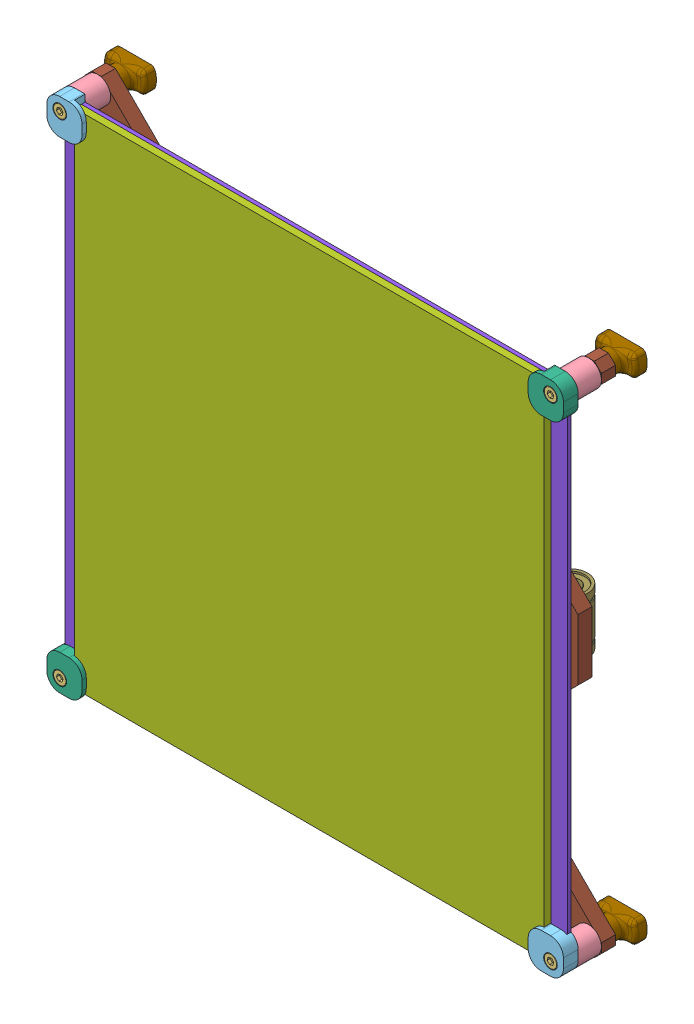
SolidWorks assembly Assembly y-carriage, configuration Valor predeterminado. Lengths in mm.
Overall size (227 224.47 49.2).
33 component instances, 14 part files, 82 mates.
Components (placement in the parent):
- Nut DIN 985 - M3-3: Nut DIN 985 - M3 [Valor predeterminado] at (-82.8364 -309.0808 -33.2819) x (0 0 -1) z (-0.999964 0.008433 0) size (4 6.35 5.5)
- Washer DIN 125A - M3-5: Washer DIN 125A - M3 [Valor predeterminado] at (-82.8364 -309.0808 -33.2819) x (0 0 -1) z (0.998771 -0.049562 0) size (0.5 7 7)
- Washer DIN 125A - M3-6: Washer DIN 125A - M3 [Valor predeterminado] at (-82.8364 -350.0808 -33.2819) x (0 0 -1) z (0.998771 -0.049562 0) size (0.5 7 7)
- Nut DIN 985 - M3-4: Nut DIN 985 - M3 [Valor predeterminado] at (-82.8364 -350.0808 -33.2819) x (0 0 -1) z (0.999227 -0.039315 0) size (4 6.35 5.5)
- Screw DIN 912 - M3 x 25 --- 18N-5: Screw DIN 912 - M3 x 25 --- 18N [Valor predeterminado] at (21.6636 -433.5808 -17.5819) x (0 0 1) z (-0.68344 0.730007 0) size (28 5.5 5.5)
- heatbed_spacer-5: heatbed_spacer [Valor predeterminado] at (-187.3364 -224.5808 -33.7819) x (-0.828895 0.559404 0) z (0 0 1) size (11 11 9.9)
- heatbed_holder_A-3: heatbed_holder_A [Valor predeterminado] at (24.1636 -436.0808 -22.0819) size (15 15 6.3)
- heatbed_holder_B-3: heatbed_holder_B [Valor predeterminado] at (-197.8364 -436.0808 -22.0819) size (15 15 6.3)
- Screw DIN 912 - M3 x 25 --- 18N-6: Screw DIN 912 - M3 x 25 --- 18N [Valor predeterminado] at (-187.3364 -433.5808 -17.5819) x (0 0 1) z (-0.68344 0.730007 0) size (28 5.5 5.5)
- heatbed_spacer-6: heatbed_spacer [Valor predeterminado] at (21.6636 -224.5808 -33.7819) x (0.643072 0.765805 0) z (0 0 1) size (11 11 9.9)
- heatbed_spacer-7: heatbed_spacer [Valor predeterminado] at (21.6636 -433.5808 -33.7819) size (11 11 9.9)
- heatbed_spacer-8: heatbed_spacer [Valor predeterminado] at (-187.3364 -433.5808 -33.7819) x (-0.784606 -0.619994 0) z (0 0 1) size (11 11 9.9)
- Glass - 214 x 200 x 3-2: Glass - 214 x 200 x 3 [Valor predeterminado] at (-82.8364 -329.0808 -22.2819) size (200 214 2.9)
- Heatbed MK2B-2: Heatbed MK2B [Valor predeterminado] at (-82.8364 -329.0808 -23.8819) size (214 214 1.6)
- Screw DIN 912 - M3 x 25 --- 18N-7: Screw DIN 912 - M3 x 25 --- 18N [Valor predeterminado] at (21.6636 -224.5808 -17.5819) x (0 0 1) z (-0.71721 0.696857 0) size (28 5.5 5.5)
- heatbed_holder_B-4: heatbed_holder_B [Valor predeterminado] at (32.1636 -222.0808 -22.0819) x (-1 0 0) z (0 0 1) size (15 15 6.3)
- heatbed_holder_A-4: heatbed_holder_A [Valor predeterminado] at (-189.8364 -222.0808 -22.0819) x (-1 0 0) z (0 0 1) size (15 15 6.3)
- Screw DIN 912 - M3 x 25 --- 18N-8: Screw DIN 912 - M3 x 25 --- 18N [Valor predeterminado] at (-187.3364 -224.5808 -17.5819) x (0 0 1) z (-0.68344 0.730007 0) size (28 5.5 5.5)
- heatbed_knob-5: heatbed_knob [Valor predeterminado] at (-187.3364 -224.5808 -39.7819) x (0 -1 0) z (-1 0 0) size (10.2 10 18)
- Nut DIN 934 - M3-5: Nut DIN 934 - M3 [Valor predeterminado] at (-187.3364 -224.5808 -43.0819) x (0 0 -1) z (0 -1 0) size (2.4 5.5 6.35)
- heatbed_knob-6: heatbed_knob [Valor predeterminado] at (21.6636 -224.5808 -39.7819) x (0 1 0) z (1 0 0) size (10.2 10 18)
- Nut DIN 934 - M3-6: Nut DIN 934 - M3 [Valor predeterminado] at (21.6636 -224.5808 -43.0819) x (0 0 -1) z (0 1 0) size (2.4 5.5 6.35)
- heatbed_knob-7: heatbed_knob [Valor predeterminado] at (21.6636 -433.5808 -39.7819) x (0 -1 0) z (-1 0 0) size (10.2 10 18)
- Nut DIN 934 - M3-7: Nut DIN 934 - M3 [Valor predeterminado] at (21.6636 -433.5808 -43.0819) x (0 0 -1) z (0 -1 0) size (2.4 5.5 6.35)
- heatbed_knob-9: heatbed_knob [Valor predeterminado] at (-187.3364 -433.5808 -39.7819) x (0 -1 0) z (-1 0 0) size (10.2 10 18)
- Nut DIN 934 - M3-9: Nut DIN 934 - M3 [Valor predeterminado] at (-187.3364 -433.5808 -43.0819) x (0 0 -1) z (0 -1 0) size (2.4 5.5 6.35)
- Y-carriage-1: Y-carriage [Valor predeterminado] at (-215.0603 -446.9296 -39.7819) size (220 220 6)
- Linear bearing LM8UU-1: Linear bearing LM8UU [Valor predeterminado] at (0.7454 -335.2735 -56.9979) x (0 -1 0) z (0.927007 0 0.375044) size (24 15 15)
- Linear bearing LM8UU-2: Linear bearing LM8UU [Valor predeterminado] at (-169.2546 -299.1293 -56.9979) x (0 -1 0) z (0.927007 0 0.375044) size (24 15 15)
- Linear bearing LM8UU-3: Linear bearing LM8UU [Valor predeterminado] at (-167.0502 -369.1363 -57.0576) x (0 -1 0) z (0.840273 0 0.542164) size (24 15 15)
- y-belt-holder-1: y-belt-holder [Valor predeterminado] at (-90.3364 -344.5808 -65.7819) x (0 1 0) z (1 0 0) size (52 27 15)
- Screw DIN 912 - M3 x 16 --- 16N-1: Screw DIN 912 - M3 x 16 --- 16N [Valor predeterminado] at (-82.8364 -309.0808 -46.7819) x (0 0 -1) z (0.998798 0.049011 0) size (19 5.5 5.5)
- Screw DIN 912 - M3 x 16 --- 16N-2: Screw DIN 912 - M3 x 16 --- 16N [Valor predeterminado] at (-82.8364 -350.0808 -46.7819) x (0 0 -1) z (0.718688 0.695333 0) size (19 5.5 5.5)
Mates (geometry in assembly coordinates):
- Concêntrico108: concentric: cylinder of assembly; cylinder of assembly; cylinder of Nut DIN 985 - M3-3 through (-82.8364 -309.0808 -25.16) axis (0 0 1) radius 1.25; cylinder of Washer DIN 125A - M3-5 through (-82.8364 -309.0808 -33.7819) axis (0 0 1) radius 1.6
- Coincidente52: coincident: plane of assembly; plane of assembly; plane of Nut DIN 985 - M3-3 through (-82.8364 -309.0808 -33.2819) normal (0 0 -1); plane of Washer DIN 125A - M3-5 through (-82.8364 -309.0808 -33.2819) normal (0 0 1)
- Coincidente53: coincident: plane of assembly; plane of assembly; plane of Washer DIN 125A - M3-6 through (-82.8364 -350.0808 -33.2819) normal (0 0 1); plane of Nut DIN 985 - M3-4 through (-82.8364 -350.0808 -33.2819) normal (0 0 -1)
- Concêntrico109: concentric: cylinder of assembly; cylinder of assembly; cylinder of Washer DIN 125A - M3-6 through (-82.8364 -350.0808 -33.7819) axis (0 0 1) radius 1.6; cylinder of Nut DIN 985 - M3-4 through (-82.8364 -350.0808 -25.16) axis (0 0 1) radius 1.25
- Coincidente56: coincident: plane of assembly; plane of assembly; plane of Screw DIN 912 - M3 x 25 --- 18N-5 through (23.6712 -431.7013 -20.5819) normal (0 0 -1); plane of heatbed_holder_A-3 through (21.6636 -433.5808 -20.5819) normal (0 0 1)
- Concêntrico112: concentric: cylinder of assembly; cylinder of assembly; cylinder of Screw DIN 912 - M3 x 25 --- 18N-5 through (21.6636 -433.5808 -17.5819) axis (0 0 1) radius 2.75; cylinder of heatbed_holder_A-3 through (21.6636 -433.5808 -20.2819) axis (0 0 1) radius 2.9
- Concêntrico114: concentric: cylinder of assembly; cylinder of assembly; cylinder of heatbed_holder_B-3 through (-187.3364 -433.5808 -20.2819) axis (0 0 1) radius 2.9; cylinder of Screw DIN 912 - M3 x 25 --- 18N-6 through (-187.3364 -433.5808 -17.5819) axis (0 0 1) radius 2.75
- Coincidente57: coincident: plane of assembly; plane of assembly; plane of heatbed_holder_B-3 through (-187.3364 -433.5808 -20.5819) normal (0 0 1); plane of Screw DIN 912 - M3 x 25 --- 18N-6 through (-185.3288 -431.7013 -20.5819) normal (0 0 -1)
- Coincidente63: coincident: plane of assembly; plane of assembly; plane of heatbed_spacer-8 through (-187.3364 -433.5808 -23.8819) normal (0 0 1); plane of Heatbed MK2B-2 through (-82.8364 -329.0808 -23.8819) normal (0 0 -1)
- Coincidente64: coincident: plane of assembly; plane of assembly; plane of Glass - 214 x 200 x 3-2 through (-82.8364 -329.0808 -22.2819) normal (0 0 -1); plane of Heatbed MK2B-2 through (-82.8364 -329.0808 -22.2819) normal (0 0 1)
- Concêntrico119: concentric: cylinder of assembly; cylinder of assembly; cylinder of Screw DIN 912 - M3 x 25 --- 18N-7 through (21.6636 -224.5808 -17.5819) axis (0 0 1) radius 2.75; cylinder of heatbed_holder_B-4 through (21.6636 -224.5808 -20.2819) axis (0 0 1) radius 2.9
- Coincidente69: coincident: plane of assembly; plane of assembly; plane of Screw DIN 912 - M3 x 25 --- 18N-7 through (23.58 -222.6085 -20.5819) normal (0 0 -1); plane of heatbed_holder_B-4 through (21.6636 -224.5808 -20.5819) normal (0 0 1)
- Coincidente70: coincident: plane of assembly; plane of assembly; plane of heatbed_holder_A-4 through (-187.3364 -224.5808 -20.5819) normal (0 0 1); plane of Screw DIN 912 - M3 x 25 --- 18N-8 through (-185.3288 -222.7013 -20.5819) normal (0 0 -1)
- Concêntrico120: concentric: cylinder of assembly; cylinder of assembly; cylinder of heatbed_holder_A-4 through (-187.3364 -224.5808 -20.2819) axis (0 0 1) radius 2.9; cylinder of Screw DIN 912 - M3 x 25 --- 18N-8 through (-187.3364 -224.5808 -17.5819) axis (0 0 1) radius 2.75
- Concêntrico121: concentric: cylinder of assembly; cylinder of assembly; cylinder of Screw DIN 912 - M3 x 25 --- 18N-6 through (-187.3364 -433.5808 -17.5819) axis (0 0 1) radius 1.5; cylinder of Heatbed MK2B-2 through (-187.3364 -433.5808 -28.1246) axis (0 0 1) radius 1.5
- Coincidente71: coincident: plane of assembly; plane of assembly; plane of heatbed_holder_B-3 through (-177.8364 -424.0808 -19.3819) normal (0 0 -1); plane of Glass - 214 x 200 x 3-2 through (-82.8364 -329.0808 -19.3819) normal (0 0 1)
- Concêntrico122: concentric: cylinder of assembly; cylinder of assembly; cylinder of Screw DIN 912 - M3 x 25 --- 18N-5 through (21.6636 -433.5808 -17.5819) axis (0 0 1) radius 1.5; cylinder of Heatbed MK2B-2 through (21.6636 -433.5808 -28.1246) axis (0 0 1) radius 1.5
- Coincidente73: coincident: plane of assembly; plane of assembly; plane of heatbed_holder_A-3 through (12.1636 -424.0808 -19.3819) normal (0 0 -1); plane of Glass - 214 x 200 x 3-2 through (-82.8364 -329.0808 -19.3819) normal (0 0 1)
- Concêntrico123: concentric: cylinder of assembly; cylinder of assembly; cylinder of Heatbed MK2B-2 through (21.6636 -224.5808 -28.1246) axis (0 0 1) radius 1.5; cylinder of Screw DIN 912 - M3 x 25 --- 18N-7 through (21.6636 -224.5808 -17.5819) axis (0 0 1) radius 1.5
- Coincidente76: coincident: plane of assembly; plane of assembly; plane of Glass - 214 x 200 x 3-2 through (-82.8364 -329.0808 -19.3819) normal (0 0 1); plane of heatbed_holder_B-4 through (12.1636 -234.0808 -19.3819) normal (0 0 -1)
- Concêntrico124: concentric: cylinder of assembly; cylinder of assembly; cylinder of Heatbed MK2B-2 through (-187.3364 -224.5808 -28.1246) axis (0 0 1) radius 1.5; cylinder of Screw DIN 912 - M3 x 25 --- 18N-8 through (-187.3364 -224.5808 -17.5819) axis (0 0 1) radius 1.5
- Coincidente78: coincident: plane of assembly; plane of assembly; plane of Glass - 214 x 200 x 3-2 through (-82.8364 -329.0808 -19.3819) normal (0 0 1); plane of heatbed_holder_A-4 through (-177.8364 -234.0808 -19.3819) normal (0 0 -1)
- Concêntrico125: concentric: cylinder of assembly; cylinder of assembly; cylinder of heatbed_knob-5 through (-187.3364 -224.5808 -54.7317) axis (0 0 1) radius 1.75; cylinder of Nut DIN 934 - M3-5 through (-187.3364 -224.5808 -44.2819) axis (0 0 1) radius 1.25
- Paralelo17: parallel: line of assembly; plane of assembly; line of heatbed_knob-5 through (-187.3364 -221.1445 -49.7819) axis (-0.866025 -0.5 0); plane of Nut DIN 934 - M3-5 through (-190.0864 -222.9931 -44.2819) normal (-0.5 0.866025 0)
- Coincidente81: coincident: plane of assembly; plane of assembly; plane of heatbed_knob-5 through (-187.3364 -224.5808 -41.8819) normal (0 0 -1); plane of Nut DIN 934 - M3-5 through (-190.0864 -222.9931 -41.8819) normal (0 0 1)
- Concêntrico128: concentric: cylinder of assembly; cylinder of assembly; cylinder of Screw DIN 912 - M3 x 25 --- 18N-8 through (-187.3364 -224.5808 -17.5819) axis (0 0 1) radius 1.5; cylinder of heatbed_knob-5 through (-187.3364 -224.5808 -54.7317) axis (0 0 1) radius 1.75
- Paralelo21: parallel: line of assembly; plane of assembly; line of heatbed_knob-6 through (21.6636 -228.017 -49.7819) axis (0.866025 0.5 0); plane of Nut DIN 934 - M3-6 through (24.4136 -226.1685 -44.2819) normal (0.5 -0.866025 0)
- Coincidente84: coincident: plane of assembly; plane of assembly; plane of heatbed_knob-6 through (21.6636 -224.5808 -41.8819) normal (0 0 -1); plane of Nut DIN 934 - M3-6 through (24.4136 -226.1685 -41.8819) normal (0 0 1)
- Concêntrico129: concentric: cylinder of assembly; cylinder of assembly; cylinder of heatbed_knob-6 through (21.6636 -224.5808 -54.7317) axis (0 0 1) radius 1.75; cylinder of Nut DIN 934 - M3-6 through (21.6636 -224.5808 -44.2819) axis (0 0 1) radius 1.25
- Paralelo22: parallel: line of assembly; plane of assembly; line of heatbed_knob-7 through (21.6636 -430.1445 -49.7819) axis (-0.866025 -0.5 0); plane of Nut DIN 934 - M3-7 through (18.9136 -431.9931 -44.2819) normal (-0.5 0.866025 0)
- Coincidente85: coincident: plane of heatbed_knob-7 through (21.6636 -433.5808 -41.8819) normal (0 0 -1); plane of Nut DIN 934 - M3-7 through (18.9136 -431.9931 -41.8819) normal (0 0 1)
- Concêntrico130: concentric: cylinder of heatbed_knob-7 through (21.6636 -433.5808 -54.7317) axis (0 0 1) radius 1.75; cylinder of Nut DIN 934 - M3-7 through (21.6636 -433.5808 -44.2819) axis (0 0 1) radius 1.25
- Concêntrico132: concentric: cylinder of assembly; cylinder of assembly; cylinder of Screw DIN 912 - M3 x 25 --- 18N-7 through (21.6636 -224.5808 -17.5819) axis (0 0 1) radius 1.5; cylinder of heatbed_knob-6 through (21.6636 -224.5808 -54.7317) axis (0 0 1) radius 1.75
- Concêntrico133: concentric: cylinder of Screw DIN 912 - M3 x 25 --- 18N-5 through (21.6636 -433.5808 -17.5819) axis (0 0 1) radius 1.5; cylinder of heatbed_knob-7 through (21.6636 -433.5808 -54.7317) axis (0 0 1) radius 1.75
- Paralelo26: parallel: line of assembly; plane of assembly; line of heatbed_knob-9 through (-187.3364 -430.1445 -49.7819) axis (-0.866025 -0.5 0); plane of Nut DIN 934 - M3-9 through (-190.0864 -431.9931 -44.2819) normal (-0.5 0.866025 0)
- Coincidente91: coincident: plane of heatbed_knob-9 through (-187.3364 -433.5808 -41.8819) normal (0 0 -1); plane of Nut DIN 934 - M3-9 through (-190.0864 -431.9931 -41.8819) normal (0 0 1)
- Concêntrico134: concentric: cylinder of heatbed_knob-9 through (-187.3364 -433.5808 -54.7317) axis (0 0 1) radius 1.75; cylinder of Nut DIN 934 - M3-9 through (-187.3364 -433.5808 -44.2819) axis (0 0 1) radius 1.25
- Concêntrico135: concentric: cylinder of Screw DIN 912 - M3 x 25 --- 18N-6 through (-187.3364 -433.5808 -17.5819) axis (0 0 1) radius 1.5; cylinder of heatbed_knob-9 through (-187.3364 -433.5808 -54.7317) axis (0 0 1) radius 1.75
- Coincidente103: coincident: plane of assembly; plane of assembly; plane of Washer DIN 125A - M3-6 through (-82.8364 -350.0808 -33.7819) normal (0 0 -1); plane of Y-carriage-1 through (-215.0603 -446.9296 -33.7819) normal (0 0 1)
- Coincidente104: coincident: plane of Washer DIN 125A - M3-5 through (-82.8364 -309.0808 -33.7819) normal (0 0 -1); plane of Y-carriage-1 through (-215.0603 -446.9296 -33.7819) normal (0 0 1)
- Concêntrico143: concentric: cylinder of assembly; cylinder of assembly; cylinder of heatbed_spacer-6 through (21.6636 -224.5808 -23.8819) axis (0 0 -1) radius 1.875; cylinder of Screw DIN 912 - M3 x 25 --- 18N-7 through (21.6636 -224.5808 -17.5819) axis (0 0 1) radius 1.5
- Coincidente105: coincident: plane of heatbed_spacer-6 through (21.6636 -224.5808 -23.8819) normal (0 0 1); plane of Heatbed MK2B-2 through (-82.8364 -329.0808 -23.8819) normal (0 0 -1)
- Concêntrico144: concentric: cylinder of assembly; cylinder of assembly; cylinder of heatbed_spacer-5 through (-187.3364 -224.5808 -23.8819) axis (0 0 -1) radius 1.875; cylinder of Screw DIN 912 - M3 x 25 --- 18N-8 through (-187.3364 -224.5808 -17.5819) axis (0 0 1) radius 1.5
- Coincidente106: coincident: plane of heatbed_spacer-5 through (-187.3364 -224.5808 -23.8819) normal (0 0 1); plane of Heatbed MK2B-2 through (-82.8364 -329.0808 -23.8819) normal (0 0 -1)
- Concêntrico150: concentric: cylinder of assembly; cylinder of assembly; cylinder of Screw DIN 912 - M3 x 25 --- 18N-6 through (-187.3364 -433.5808 -17.5819) axis (0 0 1) radius 1.5; cylinder of heatbed_spacer-8 through (-187.3364 -433.5808 -23.8819) axis (0 0 -1) radius 1.875
- Concêntrico152: concentric: cylinder of assembly; cylinder of assembly; cylinder of Screw DIN 912 - M3 x 25 --- 18N-5 through (21.6636 -433.5808 -17.5819) axis (0 0 1) radius 1.5; cylinder of heatbed_spacer-7 through (21.6636 -433.5808 -23.8819) axis (0 0 -1) radius 1.875
- Coincidente125: coincident: plane of heatbed_spacer-7 through (21.6636 -433.5808 -23.8819) normal (0 0 1); plane of Heatbed MK2B-2 through (-82.8364 -329.0808 -23.8819) normal (0 0 -1)
- Paralelo41: parallel: plane of assembly; plane of assembly; plane of Heatbed MK2B-2 through (24.1636 -222.0808 -22.2819) normal (1 0 0); plane of heatbed_holder_B-4 through (27.1636 -222.0808 -22.0819) normal (1 0 0)
- Paralelo42: parallel: plane of assembly; plane of assembly; plane of Heatbed MK2B-2 through (-189.8364 -222.0808 -22.2819) normal (-1 0 0); plane of heatbed_holder_A-4 through (-192.8364 -222.0808 -22.0819) normal (-1 0 0)
- Paralelo43: parallel: plane of assembly; plane of assembly; plane of heatbed_holder_B-3 through (-192.8364 -436.0808 -22.0819) normal (-1 0 0); plane of Heatbed MK2B-2 through (-189.8364 -222.0808 -22.2819) normal (-1 0 0)
- Paralelo44: parallel: plane of assembly; plane of assembly; plane of heatbed_holder_A-3 through (27.1636 -436.0808 -22.0819) normal (1 0 0); plane of Heatbed MK2B-2 through (24.1636 -222.0808 -22.2819) normal (1 0 0)
- Coincidente130: coincident: plane of heatbed_spacer-8 through (-187.3364 -433.5808 -33.7819) normal (0 0 -1); plane of Y-carriage-1 through (-215.0603 -446.9296 -33.7819) normal (0 0 1)
- Coincidente131: coincident: plane of heatbed_knob-7 through (21.6636 -433.5808 -39.7819) normal (0 0 1); plane of Y-carriage-1 through (-215.0603 -446.9296 -39.7819) normal (0 0 -1)
- Coincidente132: coincident: plane of heatbed_knob-9 through (-187.3364 -433.5808 -39.7819) normal (0 0 1); plane of Y-carriage-1 through (-215.0603 -446.9296 -39.7819) normal (0 0 -1)
- Coincidente133: coincident: plane of heatbed_knob-6 through (21.6636 -224.5808 -39.7819) normal (0 0 1); plane of Y-carriage-1 through (-215.0603 -446.9296 -39.7819) normal (0 0 -1)
- Coincidente134: coincident: plane of heatbed_knob-5 through (-187.3364 -224.5808 -39.7819) normal (0 0 1); plane of Y-carriage-1 through (-215.0603 -446.9296 -39.7819) normal (0 0 -1)
- Paralelo45: parallel: plane of assembly; plane of assembly; plane of Heatbed MK2B-2 through (-189.8364 -222.0808 -22.2819) normal (0 1 0); plane of heatbed_knob-6 through (21.6636 -220.0808 -72.6832) normal (0 1 0)
- Paralelo46: parallel: plane of assembly; plane of assembly; plane of Heatbed MK2B-2 through (-189.8364 -222.0808 -22.2819) normal (0 1 0); plane of heatbed_knob-5 through (-187.3364 -220.0808 -72.6832) normal (0 1 0)
- Paralelo47: parallel: plane of Heatbed MK2B-2 through (-189.8364 -436.0808 -22.2819) normal (0 -1 0); plane of heatbed_knob-7 through (21.6636 -438.0808 -72.6832) normal (0 -1 0)
- Paralelo48: parallel: plane of Heatbed MK2B-2 through (-189.8364 -436.0808 -22.2819) normal (0 -1 0); plane of heatbed_knob-9 through (-187.3364 -438.0808 -72.6832) normal (0 -1 0)
- Coincidente139: coincident: plane of assembly; plane of assembly; plane of Glass - 214 x 200 x 3-2 through (-82.8364 -329.0808 -22.2819) normal (-1 0 0); plane of Heatbed MK2B-2 through (-82.8364 -329.0808 -23.8819) normal (1 0 0)
- Coincidente140: coincident: plane of assembly; plane of assembly; plane of Glass - 214 x 200 x 3-2 through (-82.8364 -329.0808 -22.2819) normal (0 -1 0); plane of Heatbed MK2B-2 through (-82.8364 -329.0808 -23.8819) normal (0 1 0)
- Coincidente142: coincident: plane of Heatbed MK2B-2 through (-82.8364 -329.0808 -23.8819) normal (1 0 0); plane of Y-carriage-1 through (-82.8364 -446.9296 -39.7819) normal (1 0 0)
- Coincidente143: coincident: plane of Heatbed MK2B-2 through (-82.8364 -329.0808 -23.8819) normal (0 1 0); plane of Y-carriage-1 through (-215.0603 -329.0808 -39.7819) normal (0 1 0)
- Coincidente144: coincident: plane of Y-carriage-1 through (-215.0603 -329.7179 -39.7819) normal (0 1 0); plane of Linear bearing LM8UU-1 through (0.7454 -329.7179 -56.9979) normal (0 1 0)
- Coincidente145: coincident: line of Y-carriage-1 through (-2.8364 -318.2179 -39.7819) axis (0 -1 0); cylinder of Linear bearing LM8UU-1 through (2.1636 -329.7179 -45.3721) axis (0 -1 0) radius 7.5
- Coincidente146: coincident: line of Y-carriage-1 through (7.1636 -341.2179 -39.7819) axis (0 1 0); cylinder of Linear bearing LM8UU-1 through (2.1636 -329.7179 -45.3721) axis (0 -1 0) radius 7.5
- Coincidente147: coincident: plane of Y-carriage-1 through (-215.0603 -293.5737 -39.7819) normal (0 -1 0); plane of Linear bearing LM8UU-2 through (-169.2546 -293.5737 -56.9979) normal (0 1 0)
- Coincidente148: coincident: plane of Y-carriage-1 through (-215.0603 -363.5808 -39.7819) normal (0 1 0); plane of Linear bearing LM8UU-3 through (-167.0502 -363.5808 -57.0576) normal (0 1 0)
- Coincidente149: coincident: line of Y-carriage-1 through (-172.8364 -352.0808 -39.7819) axis (0 -1 0); cylinder of Linear bearing LM8UU-3 through (-167.8364 -363.5808 -45.3721) axis (0 -1 0) radius 7.5
- Coincidente150: coincident: line of Y-carriage-1 through (-172.8364 -282.0737 -39.7819) axis (0 -1 0); cylinder of Linear bearing LM8UU-2 through (-167.8364 -293.5737 -45.3721) axis (0 -1 0) radius 7.5
- Coincidente151: coincident: line of Y-carriage-1 through (-162.8364 -305.0737 -39.7819) axis (0 1 0); cylinder of Linear bearing LM8UU-2 through (-167.8364 -293.5737 -45.3721) axis (0 -1 0) radius 7.5
- Coincidente152: coincident: line of Y-carriage-1 through (-162.8364 -375.0808 -39.7819) axis (0 1 0); cylinder of Linear bearing LM8UU-3 through (-167.8364 -363.5808 -45.3721) axis (0 -1 0) radius 7.5
- Coincidente153: coincident: plane of Y-carriage-1 through (-215.0603 -446.9296 -39.7819) normal (0 0 -1); plane of y-belt-holder-1 through (-91.3364 -354.5808 -39.7819) normal (0 0 1)
- Coincidente154: coincident: plane of Y-carriage-1 through (-82.8364 -446.9296 -39.7819) normal (1 0 0); plane of y-belt-holder-1 through (-82.8364 -344.5808 -65.7819) normal (-1 0 0)
- Coincidente155: coincident: plane of Y-carriage-1 through (-215.0603 -309.0808 -39.7819) normal (0 1 0); plane of y-belt-holder-1 through (-90.3364 -309.0808 -65.7819) normal (0 1 0)
- Concêntrico153: concentric: cylinder of Nut DIN 985 - M3-3 through (-82.8364 -309.0808 -25.16) axis (0 0 1) radius 1.25; cylinder of Y-carriage-1 through (-82.8364 -309.0808 -33.7819) axis (0 0 -1) radius 1.5
- Concêntrico154: concentric: cylinder of Nut DIN 985 - M3-4 through (-82.8364 -350.0808 -25.16) axis (0 0 1) radius 1.25; cylinder of Y-carriage-1 through (-82.8364 -350.0808 -33.7819) axis (0 0 -1) radius 1.5
- Concêntrico155: concentric: cylinder of assembly; cylinder of assembly; cylinder of Nut DIN 985 - M3-3 through (-82.8364 -309.0808 -25.16) axis (0 0 1) radius 1.25; cylinder of Screw DIN 912 - M3 x 16 --- 16N-1 through (-82.8364 -309.0808 -46.7819) axis (0 0 -1) radius 1.5
- Coincidente158: coincident: plane of assembly; plane of assembly; plane of y-belt-holder-1 through (-82.8364 -306.0808 -43.7819) normal (0 0 -1); plane of Screw DIN 912 - M3 x 16 --- 16N-1 through (-82.9711 -306.3341 -43.7819) normal (0 0 1)
- Concêntrico156: concentric: cylinder of assembly; cylinder of assembly; cylinder of Nut DIN 985 - M3-4 through (-82.8364 -350.0808 -25.16) axis (0 0 1) radius 1.25; cylinder of Screw DIN 912 - M3 x 16 --- 16N-2 through (-82.8364 -350.0808 -46.7819) axis (0 0 -1) radius 1.5
- Coincidente159: coincident: plane of assembly; plane of assembly; plane of y-belt-holder-1 through (-82.8364 -350.0808 -43.7819) normal (0 0 -1); plane of Screw DIN 912 - M3 x 16 --- 16N-2 through (-84.7485 -348.1044 -43.7819) normal (0 0 1)
